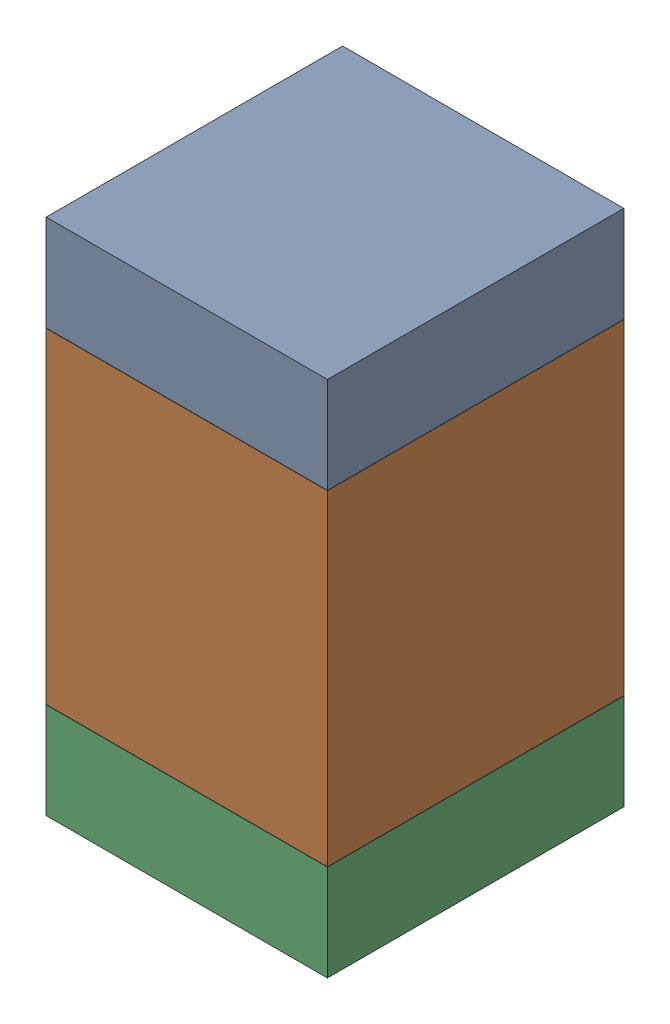
SolidWorks assembly R11, configuration Default. Lengths in mm.
Overall size (0.95 1.75 1).
6 component instances, 2 part files, 0 mates.
Components (placement in the parent):
- 6575495072-1: 6575495072 [Default] at (1.651 17.7305 0) size (0.95 0.32 1)
  - Extruded_6-1: Extruded_6 [Default] at origin size (0.95 0.32 1)
- 6575494912-1: 6575494912 [Default] at (1.651 17.018 0) size (0.95 1.1 1)
  - Extruded_7-1: Extruded_7 [Default] at origin size (0.95 1.1 1)
- 6575495072-2: 6575495072 [Default] at (1.651 16.3055 0) size (0.95 0.32 1)
  - Extruded_6-1: Extruded_6 [Default] at origin size (0.95 0.32 1)
